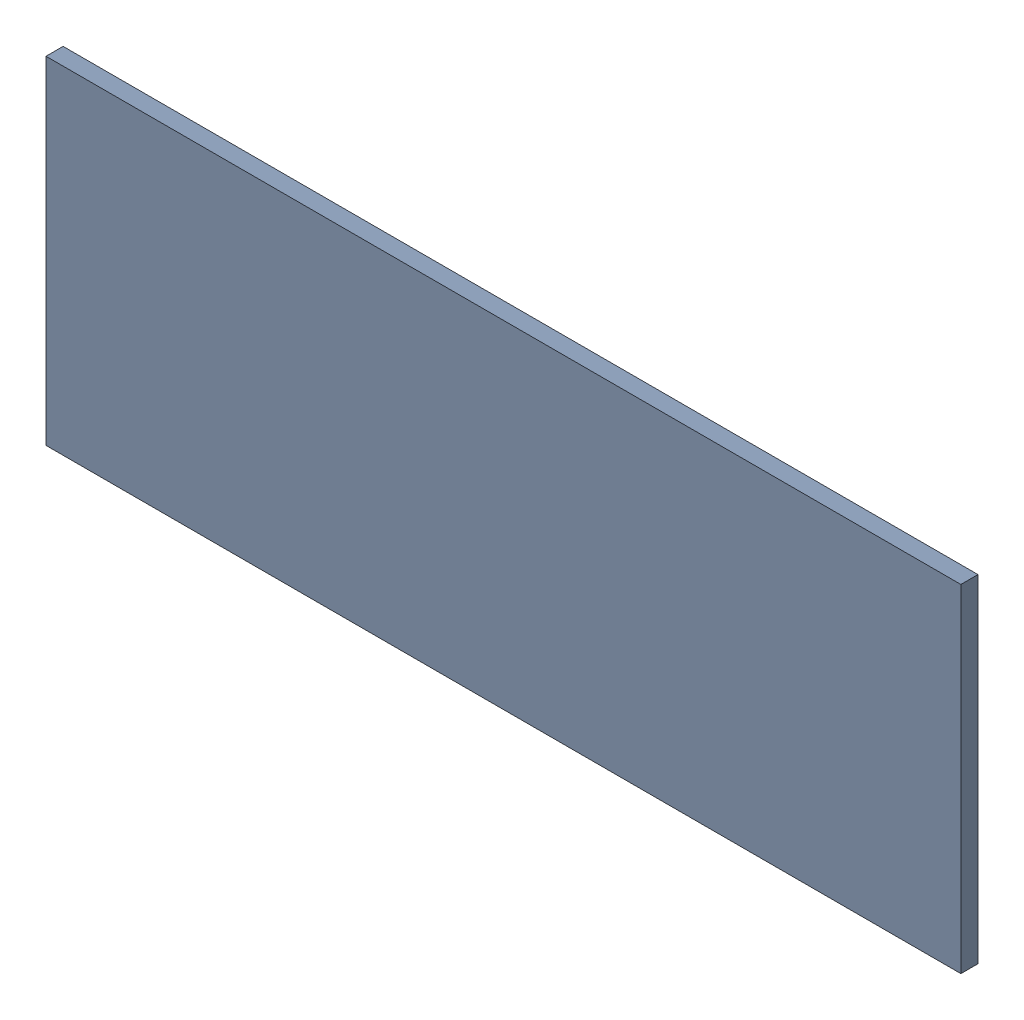
SolidWorks assembly Pad RAK4600-8(14.5mm,18.75mm) on Top Layer, configuration Predeterminado. Lengths in mm.
Overall size (1.9 0.7 0.04).
2 component instances, 1 part files, 0 mates.
Components (placement in the parent):
- Pad RAK4600-8(14.5mm,18.75mm) on Top Layer-1-1: Pad RAK4600-8(14.5mm,18.75mm) on Top Layer-1 [Predeterminado] at (-68.317 -44.187 -0.0457) size (1.9 0.7 0.04)
  - Pad RAK4600-8(14.5mm,18.75mm) on Top Layer-Part-1-1: Pad RAK4600-8(14.5mm,18.75mm) on Top Layer-Part-1 [Predeterminado] at origin size (1.9 0.7 0.04)
